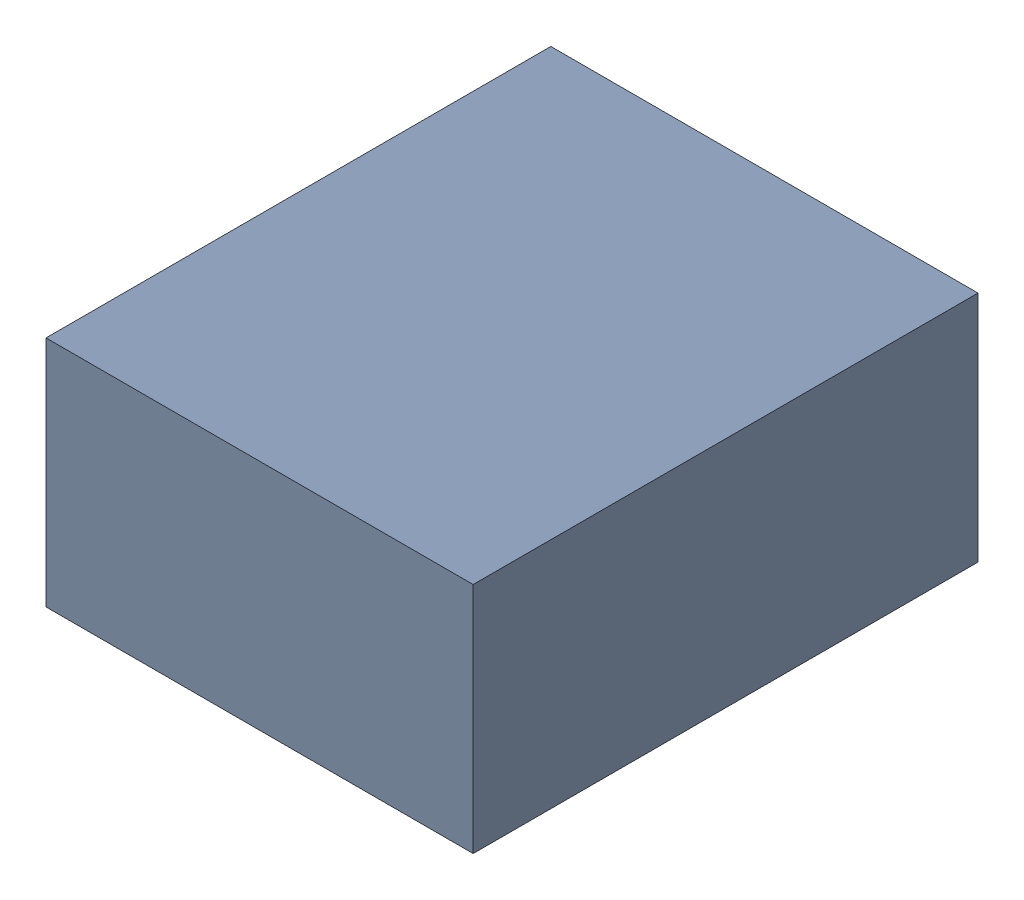
SolidWorks assembly C10, configuration Standard. Lengths in mm.
Overall size (1.1 0.6 1.3).
2 component instances, 1 part files, 0 mates.
Components (placement in the parent):
- 885542240-1: 885542240 [Standard] at (9.75 0.55 0) size (1.1 0.6 1.3)
  - Extruded_28-1: Extruded_28 [Standard] at origin size (1.1 0.6 1.3)
